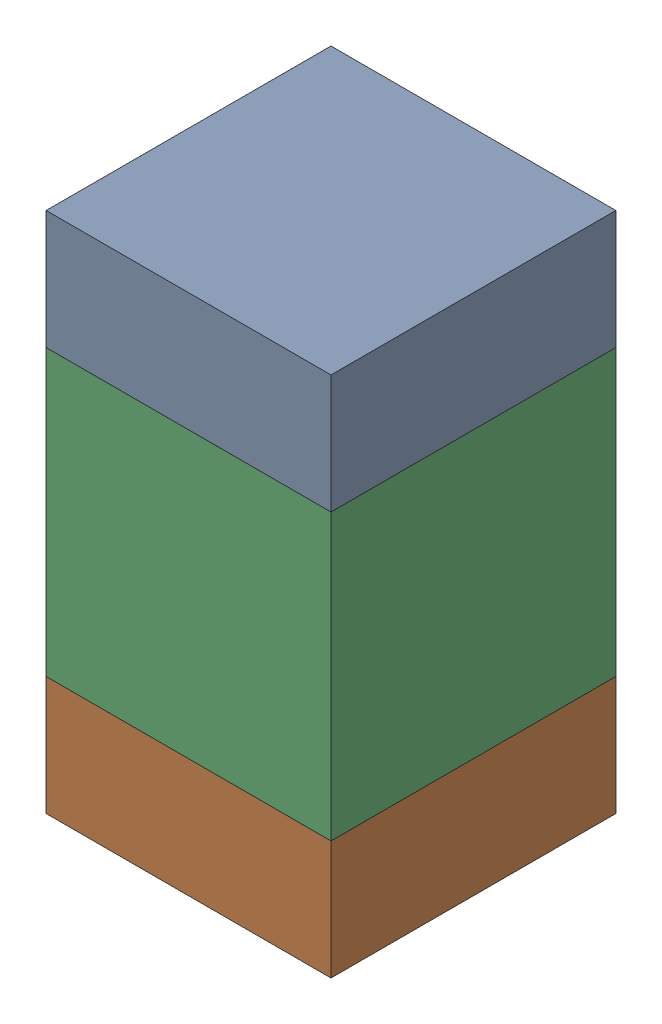
SolidWorks assembly C312_1PCB, configuration Default. Lengths in mm.
Overall size (0.6 1.1 0.6).
6 component instances, 2 part files, 0 mates.
Components (placement in the parent):
- 854785296-1: 854785296 [Default] at (127.3343 112.375 0) size (0.6 0.25 0.6)
  - Extruded_10-1: Extruded_10 [Default] at origin size (0.6 0.25 0.6)
- 854785296-2: 854785296 [Default] at (127.3343 111.525 0) size (0.6 0.25 0.6)
  - Extruded_10-1: Extruded_10 [Default] at origin size (0.6 0.25 0.6)
- 761606048-1: 761606048 [Default] at (127.3343 111.95 0) size (0.6 0.6 0.6)
  - Extruded_9-1: Extruded_9 [Default] at origin size (0.6 0.6 0.6)
